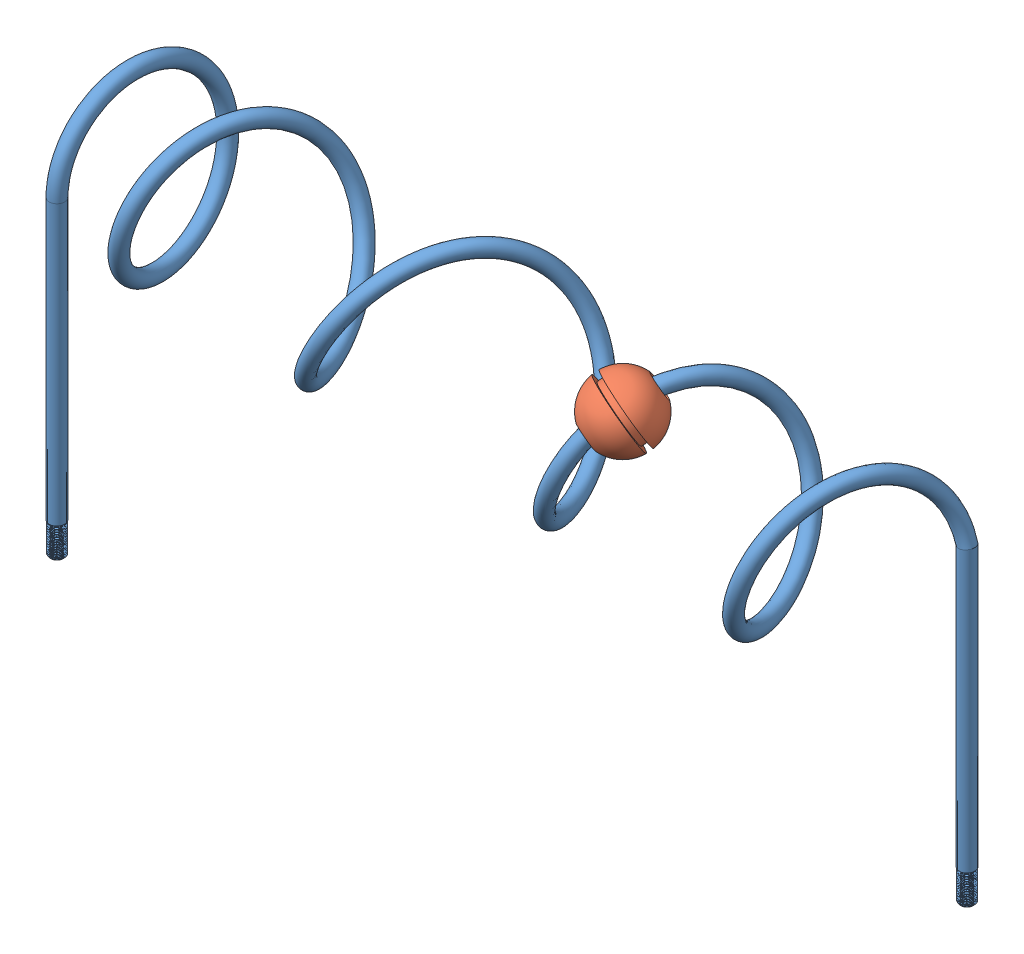
SolidWorks assembly Sestava1, configuration Výchozí. Lengths in mm.
Overall size (248.68 137.71 56.53).
2 component instances, 2 part files, 2 mates.
Components (placement in the parent):
- krivka_spirala_01_cela_krivka-1: krivka_spirala_01_cela_krivka [Výchozí] at origin size (248.68 127.68 55.52)
- kulicka_01-1: kulicka_01 [Výchozí] at (174.6916 49.9099 4.2429) x (-0.32745 -0.704643 -0.629488) z (-0.85966 0.498659 -0.111012) size (21.91 20.49 21.91)
Mates (geometry in assembly coordinates):
- Vazba Trajektorie3: path: point of kulicka_01-1; curve of krivka_spirala_01_cela_krivka-1
- Vazba Trajektorie4: path: point of kulicka_01-1; curve of krivka_spirala_01_cela_krivka-1
